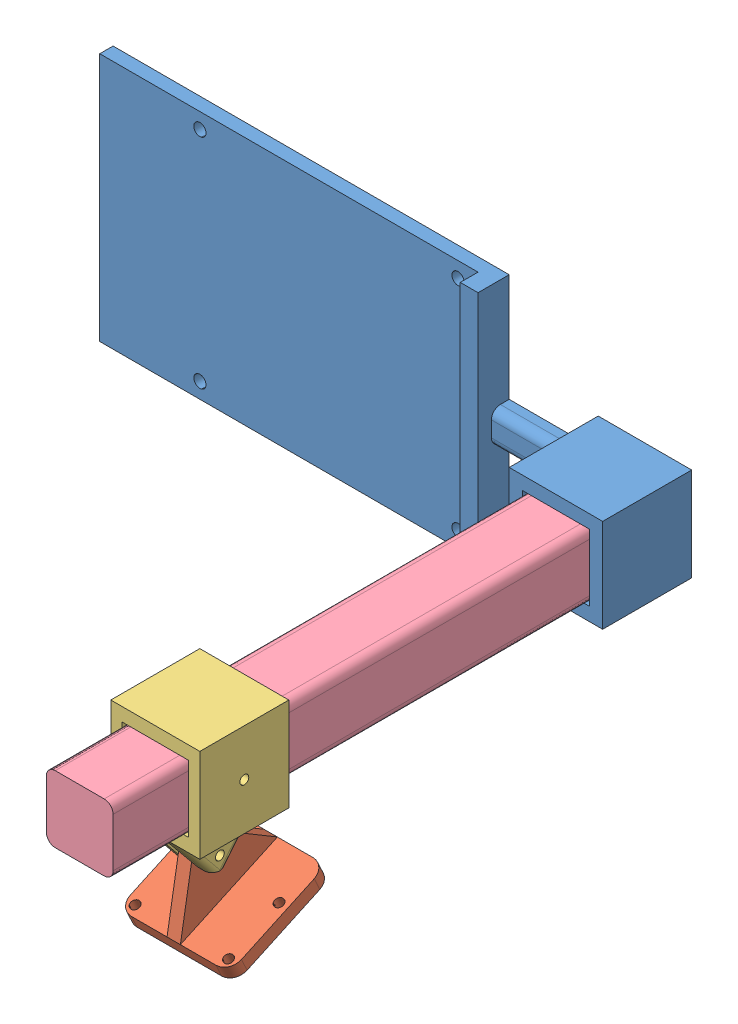
SolidWorks assembly Assem1, configuration Default. Lengths in mm.
Overall size (132 64.15 127).
4 component instances, 4 part files, 6 mates.
Components (placement in the parent):
- Part4-1: Part4 [Default] at (107.8613 63.1843 90.3981) size (130 56 20)
- Part1-1: Part1 [Default] at (107.8613 34.7891 185.3799) x (1 0 0) z (0 -0.907935 -0.419111) size (25 24 18)
- Part2-1: Part2 [Default] at (107.8613 52.6843 190.4092) x (-1 0 0) z (0 1 0) size (20 20 31)
- Part3-1: Part3 [Default] at (107.8613 63.1843 90.3981) size (15 15 127)
Mates (geometry in assembly coordinates):
- Coincident2: coincident anti-aligned: plane of Part4-1 through (115.3613 70.6843 90.3981) normal (0 -1 0); plane of Part3-1 through (115.3613 70.6843 217.3981) normal (0 1 0)
- Coincident3: coincident anti-aligned: plane of Part4-1 through (115.3613 55.6843 90.3981) normal (-1 0 0); plane of Part3-1 through (115.3613 55.6843 217.3981) normal (1 0 0)
- Coincident4: coincident aligned: plane of Part4-1 through (107.8613 63.1843 90.3981) normal (0 0 -1); plane of Part3-1 through (107.8613 63.1843 90.3981) normal (0 0 -1)
- Coincident30: coincident anti-aligned: plane of Part2-1 through (100.3613 55.6843 179.4092) normal (0 1 0); plane of Part3-1 through (115.3613 55.6843 217.3981) normal (0 -1 0)
- Coincident31: coincident anti-aligned: plane of Part2-1 through (115.3613 70.6843 179.4092) normal (-1 0 0); plane of Part3-1 through (115.3613 55.6843 217.3981) normal (1 0 0)
- Coincident33: coincident aligned: circle of Part1-1; circle of Part2-1
